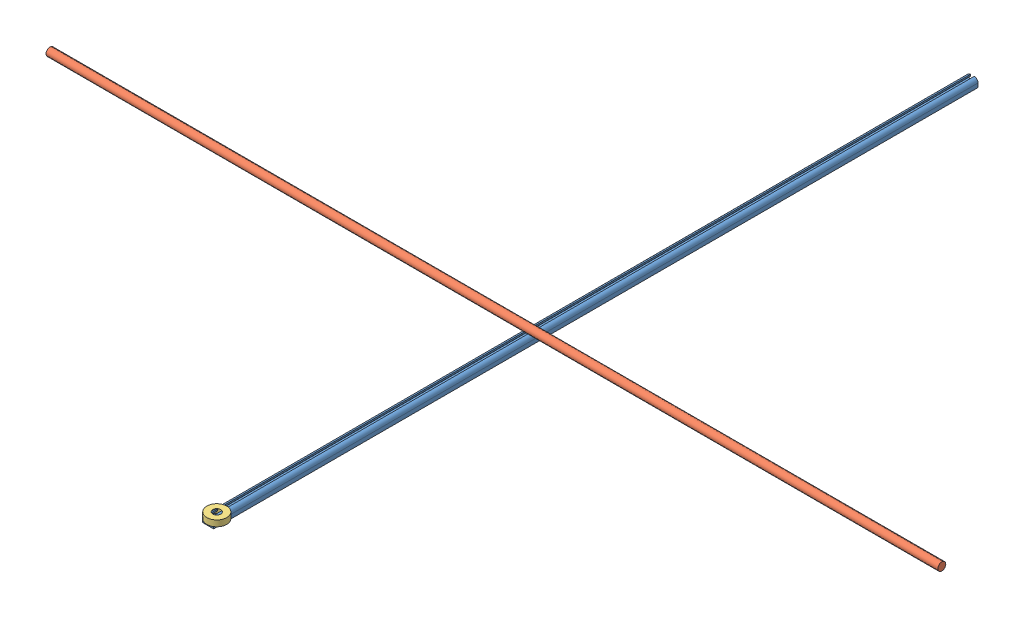
SolidWorks assembly Assem1, configuration Default. Lengths in mm.
Overall size (711.2 19.64 610.84).
3 component instances, 3 part files, 0 mates.
Components (placement in the parent):
- Twack-1: Twack [Default] at (-47.4252 11.8643 -288.8964) size (8.89 6.3 609.6)
- Metal rod 2ft-1: Metal rod 2ft [Default] at (-421.4389 26.7457 72.7188) size (711.2 6.35 6.35)
- Bearing standin-1: Bearing standin [Default] at (-47.1169 11.919 314.0052) size (15.88 4.76 15.88)
